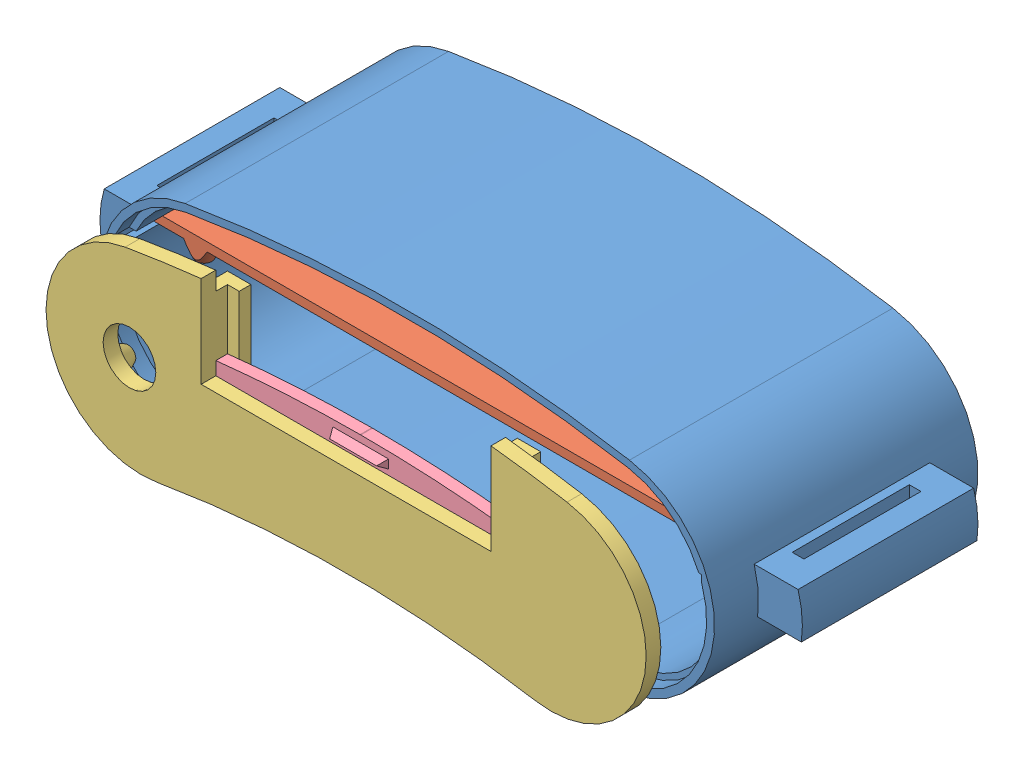
SolidWorks assembly Assemblage3, configuration Défaut. Lengths in mm.
Overall size (240 75.96 110.69).
4 component instances, 4 part files, 6 mates.
Components (placement in the parent):
- box2.1-1: box2.1 [Défaut] at (-45.7539 -400.1583 195) size (240 75.96 90)
- plaqueCapteur-1: plaqueCapteur [Défaut] at (-45.9954 21.8417 243.7084) x (1 0 0) z (0 -1 0) size (201 71 8)
- Socle1-1: Socle1 [Défaut] at (-45.7539 -400.1583 300.6925) x (1 0.000482 0) z (0 0 1) size (205.07 68.3 13)
- trape1-1: trape1 [Défaut] at (-111.1454 -136.0547 296.6925) x (1 0.000482 0) z (0 0 1) size (99.02 34 6.6)
Mates (geometry in assembly coordinates):
- Coïncidente1: coincident anti-aligned: plane of box2.1-1 through (54.9515 21.8417 290) normal (-1 0 0); plane of plaqueCapteur-1 through (54.9515 18.8417 273.0079) normal (1 0 0)
- Coïncidente2: coincident anti-aligned: line of box2.1-1 through (54.9515 21.8417 285) axis (0 0 -1); line of plaqueCapteur-1 through (54.9515 21.8417 200.0079) axis (0 0 1)
- Coïncidente5: coincident anti-aligned: line of Socle1-1 through (-95.3864 38.3533 296.6925) axis (0.000482 -1 0); line of trape1-1 through (-95.3615 -13.398 296.6925) axis (-0.000482 1 0)
- Coaxiale1: concentric aligned: circle of box2.1-1; circle of Socle1-1
- Coaxiale2: concentric aligned: circle of box2.1-1; circle of Socle1-1
- Coïncidente6: coincident aligned: line of Socle1-1 through (3.6642 -16.5989 296.6925) axis (-0.000482 1 0); line of trape1-1 through (3.6626 -13.3503 296.6925) axis (-0.000482 1 0)
